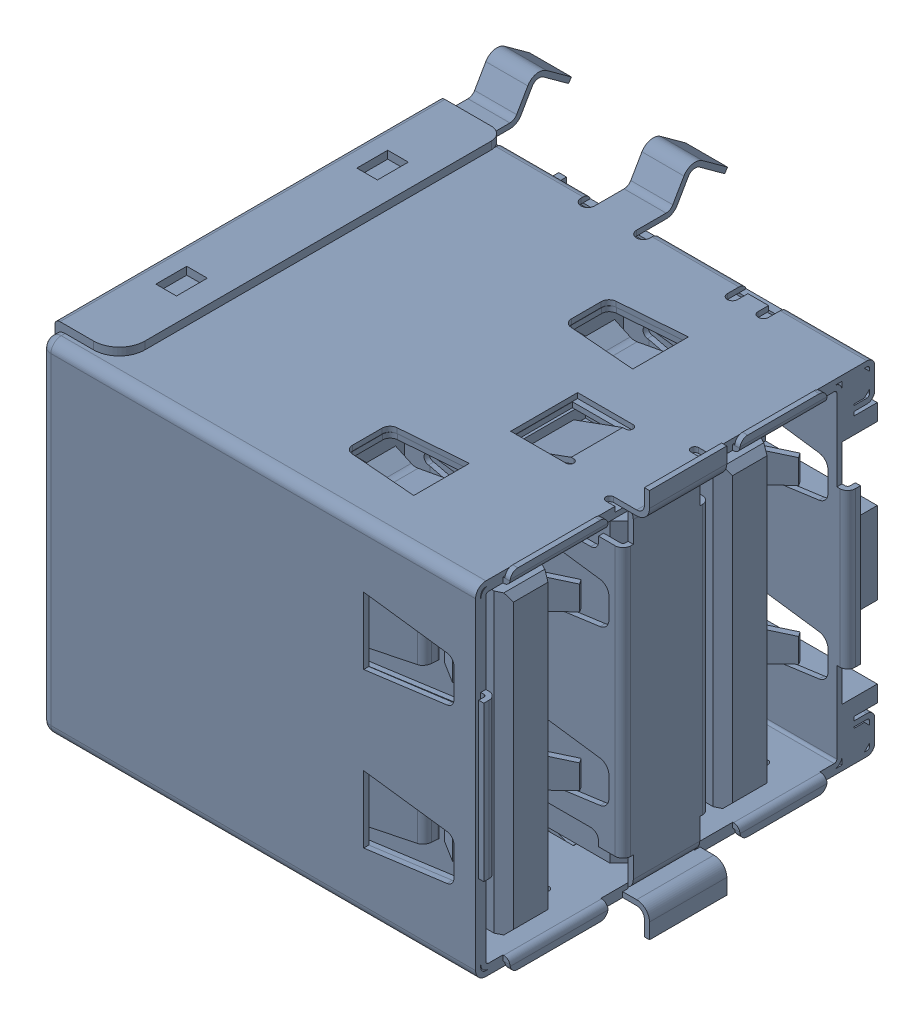
SolidWorks assembly USB_Ports_0,1_USB1, configuration Default. Lengths in mm.
Overall size (18 15.6 18.75).
2 component instances, 1 part files, 0 mates.
Components (placement in the parent):
- 672984090-1: 672984090 [Default] at (183.97 74.9299 8) x (0 1 0) z (1 0 0) size (15.6 18.75 18)
  - Open CASCADE STEP translator 6.2 1.82.1.1-1: Open CASCADE STEP translator 6.2 1.82.1.1 [Default] at origin size (15.6 18.75 18)
